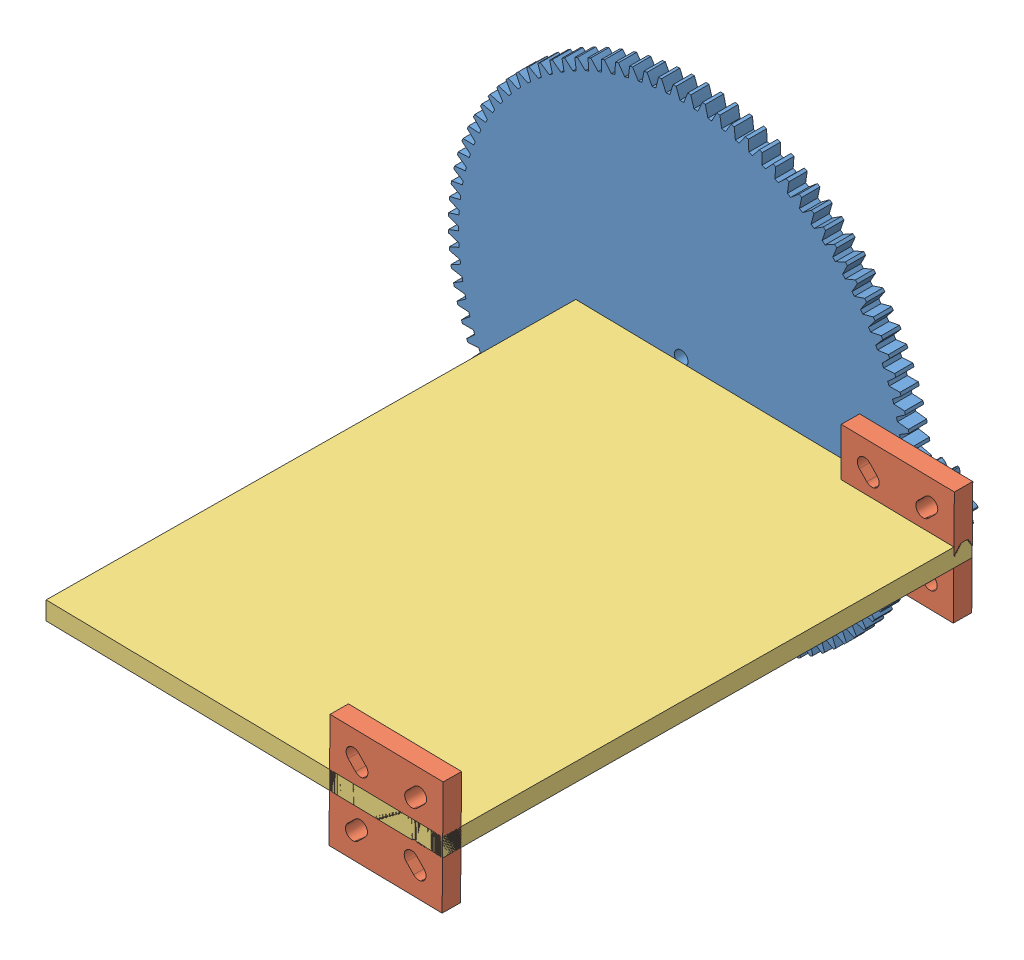
SolidWorks assembly assembly, configuration Default. Lengths in mm.
Overall size (132.05 128.68 122.85).
5 component instances, 3 part files, 13 mates.
Components (placement in the parent):
- spur gear_am-4: spur gear_am [Metric - Spur gear 1M 100T 20PA 4FW ---S100N75H50L3N] at (0 0 -4) x (0 0 1) z (-0.950144 0.311812 0) size (4 101.97 101.97)
- spur gear_am-6: spur gear_am [Metric - Spur gear 1M 10T 20PA 4FW ---S10N75H50L3N] at (55 0 -4) x (0 0 1) z (-0.823629 0.567129 0) size (4 11.48 12)
- mount holes-1: mount holes [Default] at (55.0584 -0.0405 7.745) x (0.008714 -0.000078 -0.999962) z (-0.99992 0.009183 -0.008715) size (4 25 25)
- chassis-1: chassis [Default] at (66.5901 -0.1466 118.8497) x (0.008714 -0.000078 -0.999962) z (-0.99992 0.009183 -0.008715) size (115 4 87.63)
- mount holes-10: mount holes [Default] at (54.1259 -0.0322 114.7409) x (-0.008714 0.000078 0.999962) z (-0.99992 0.009183 -0.008715) size (4 25 25)
Mates (geometry in assembly coordinates):
- Concentric3: concentric: cylinder of spur gear_am-4 through (0 0 46.0001) axis (0 0 -1) radius 1.5
- Concentric4: concentric: cylinder of spur gear_am-6 through (55 0 46.0001) axis (0 0 -1) radius 1.5
- Coincident15: coincident aligned: plane of assembly through (0 0 0) normal (0 0 1); plane of spur gear_am-4 through (0 0 0) normal (0 0 1)
- Coincident16: coincident aligned: plane of spur gear_am-6 through (55 0 0) normal (0 0 1)
- GearMate3: gear = 30 : 3 mm: cylinder of spur gear_am-6 through (54.9566 0 46.0001) axis (0 0 -1) radius 1.5; cylinder of spur gear_am-4 through (0 0 46.0001) axis (0 0 -1) radius 1.5
- Parallel1: parallel aligned: plane of mount holes-10 through (66.5901 -0.1466 118.8497) normal (0.99992 -0.009183 0.008715); plane of chassis-1 through (66.5717 -2.1466 118.8497) normal (0.99992 -0.009183 0.008715)
- Width2: width anti-aligned: plane of mount holes-1 through (55.208 12.4586 3.7452) normal (0.009183 0.999958 0.000002); plane of chassis-1 through (54.9784 -12.5403 3.7451) normal (-0.009183 -0.999958 -0.000002); plane of mount holes-1 through (66.5717 -2.1466 118.8497) normal (-0.009183 -0.999958 -0.000002); plane of chassis-1 through (66.6084 1.8533 118.8497) normal (0.009183 0.999958 0.000002)
- Coincident18: coincident aligned: plane of mount holes-1 through (55.0932 -0.0408 3.7452) normal (0.008714 -0.000078 -0.999962); plane of chassis-1 through (67.5739 -2.1555 3.8541) normal (0.008714 -0.000078 -0.999962)
- Coincident19: coincident aligned: plane of mount holes-1 through (67.5922 -0.1556 3.8541) normal (0.99992 -0.009183 0.008715); plane of chassis-1 through (66.5717 -2.1466 118.8497) normal (0.99992 -0.009183 0.008715)
- Coincident31: coincident aligned: plane of chassis-1 through (66.5717 -2.1466 118.8497) normal (-0.008714 0.000078 0.999962); plane of mount holes-10 through (54.0911 -0.0319 118.7408) normal (-0.008714 0.000078 0.999962)
- Coincident32: coincident aligned: plane of chassis-1 through (66.5717 -2.1466 118.8497) normal (0.99992 -0.009183 0.008715); plane of mount holes-10 through (66.5901 -0.1466 118.8497) normal (0.99992 -0.009183 0.008715)
- Width3: width aligned: plane of mount holes-10 through (53.9763 -12.5313 118.7408) normal (-0.009183 -0.999958 -0.000002); plane of chassis-1 through (54.2059 12.4676 118.7408) normal (0.009183 0.999958 0.000002); plane of mount holes-10 through (66.5717 -2.1466 118.8497) normal (-0.009183 -0.999958 -0.000002); plane of chassis-1 through (66.6084 1.8533 118.8497) normal (0.009183 0.999958 0.000002)
- Parallel8: parallel aligned: plane of chassis-1 through (66.5717 -2.1466 118.8497) normal (0.99992 -0.009183 0.008715); plane of mount holes-10 through (66.5901 -0.1466 118.8497) normal (0.99992 -0.009183 0.008715)
